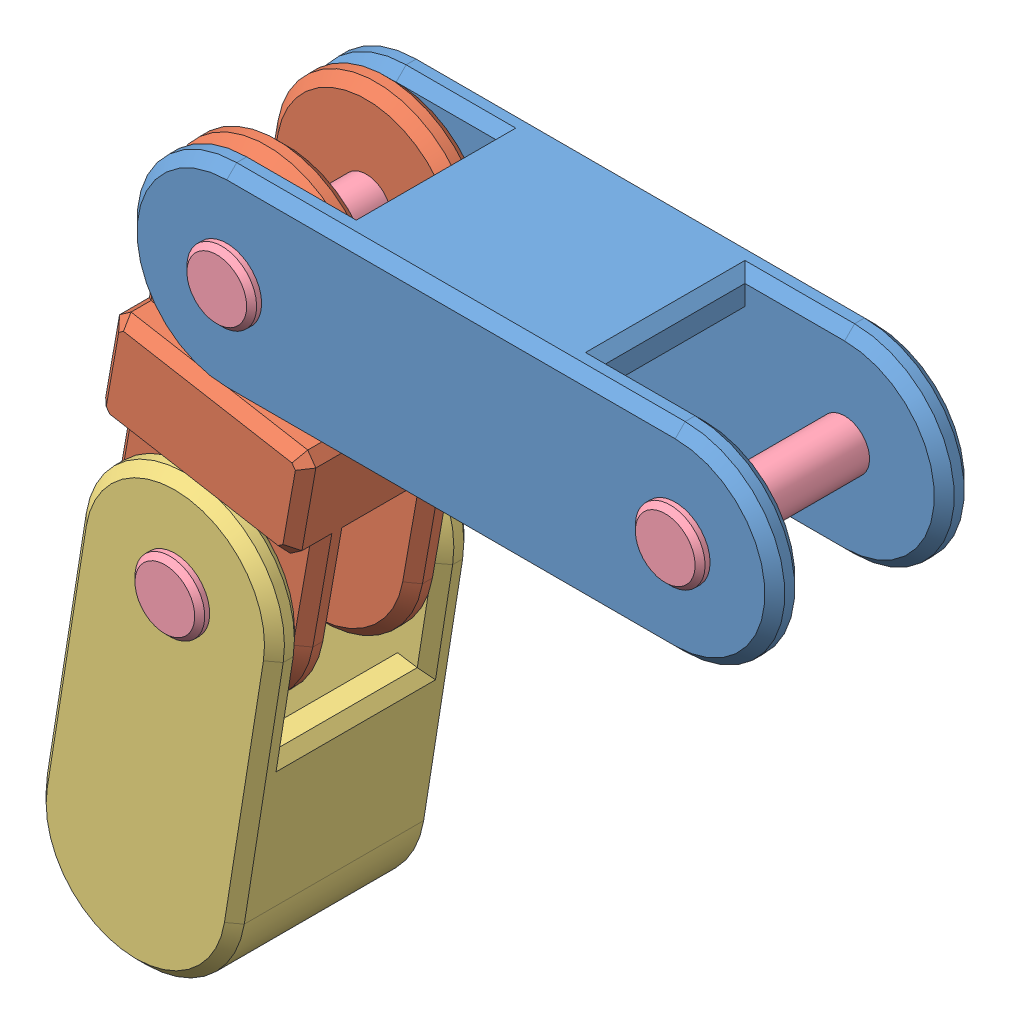
SolidWorks assembly Robot_Finger, configuration Default. Lengths in mm.
Overall size (75.56 77.26 22).
6 component instances, 4 part files, 18 mates.
Components (placement in the parent):
- finger_inner-1: finger_inner [Default] at (-22.5 0 0) x (-1 0 0) z (0 0 -1) size (65 20 20)
- finger_middle-1: finger_middle [Default] at (-47.6047 -14.7721 0) x (-0.173648 -0.984808 0) z (0 0 -1) size (50 20 20)
- finger_top-1: finger_top [Default] at (-52.1649 -41.8903 0) x (-0.156434 -0.987688 0) z (0 0 -1) size (45 20 20)
- finger_connector-1: finger_connector [Default] x (1 0 0) z (0 0 -1) size (7 7 22)
- finger_connector-2: finger_connector [Default] at (-45 0 0) x (0.984808 -0.173648 0) z (0 0 -1) size (7 7 22)
- finger_connector-3: finger_connector [Default] at (-50.2094 -29.5442 0) x (-0.156434 -0.987688 0) z (0 0 -1) size (7 7 22)
Mates (geometry in assembly coordinates):
- Concentric1: concentric: cylinder of finger_inner-1 through (-45 0 10) axis (0 0 -1) radius 2.5; cylinder of finger_middle-1 through (-45 0 10) axis (0 0 -1) radius 2.5
- Coincident1: coincident: plane of finger_inner-1 through (-22.5 0 0) normal (0 0 -1); plane of finger_middle-1 through (-47.6047 -14.7721 0) normal (0 0 -1)
- Concentric2: concentric: cylinder of finger_middle-1 through (-50.2094 -29.5442 10) axis (0 0 -1) radius 2.5; cylinder of finger_top-1 through (-50.2094 -29.5442 10) axis (0 0 -1) radius 2.5
- Coincident2: coincident: plane of finger_inner-1 through (-22.5 0 0) normal (0 0 -1); plane of finger_top-1 through (-52.1649 -41.8903 0) normal (0 0 -1)
- Concentric3: concentric: cylinder of finger_inner-1 through (0 0 10) axis (0 0 -1) radius 2.5; cylinder of finger_connector-1 through (0 0 -10) axis (0 0 1) radius 2.5
- Concentric4: concentric: cylinder of finger_inner-1 through (-45 0 10) axis (0 0 -1) radius 2.5; cylinder of finger_connector-2 through (-45 0 -10) axis (0 0 1) radius 2.5
- Concentric5: concentric: cylinder of finger_top-1 through (-50.2094 -29.5442 10) axis (0 0 -1) radius 2.5; cylinder of finger_connector-3 through (-50.2094 -29.5442 -10) axis (0 0 1) radius 2.5
- LimitAngle1: limit planar angle = 1.396263 rad: plane of finger_inner-1 through (-22.5 0 0) normal (-1 0 0); plane of finger_middle-1
- LimitAngle2: limit planar angle = 0.017453 rad: plane of finger_middle-1; plane of finger_top-1
- Coincident36: coincident: plane of finger_inner-1 through (0 0 -10) normal (0 0 -1); plane of finger_connector-1 through (0 0 -10) normal (0 0 1)
- Coincident37: coincident: plane of finger_inner-1 through (0 0 -10) normal (0 0 -1); plane of finger_connector-2 through (-45 0 -10) normal (0 0 1)
- Coincident38: coincident: plane of finger_top-1 through (-50.2094 -29.5442 -10) normal (0 0 -1); plane of finger_connector-3 through (-50.2094 -29.5442 -10) normal (0 0 1)
- Coincident39: coincident: plane of finger_connector-1 through (0 0 0) normal (0 0 -1); plane of assembly through (0 0 0) normal (0 0 1)
- Coincident40: coincident: plane of finger_connector-1 through (0 0 0) normal (0 -1 0); plane of assembly through (0 0 0) normal (0 1 0)
- Coincident41: coincident: plane of finger_connector-1; plane of assembly through (0 0 0) normal (1 0 0)
- Coincident42: coincident: plane of finger_top-1; plane of finger_connector-3
- Coincident43: coincident: plane of finger_middle-1; plane of finger_connector-2
- Coincident44: coincident: plane of finger_inner-1; plane of finger_connector-1 through (0 0 0) normal (0 -1 0)
